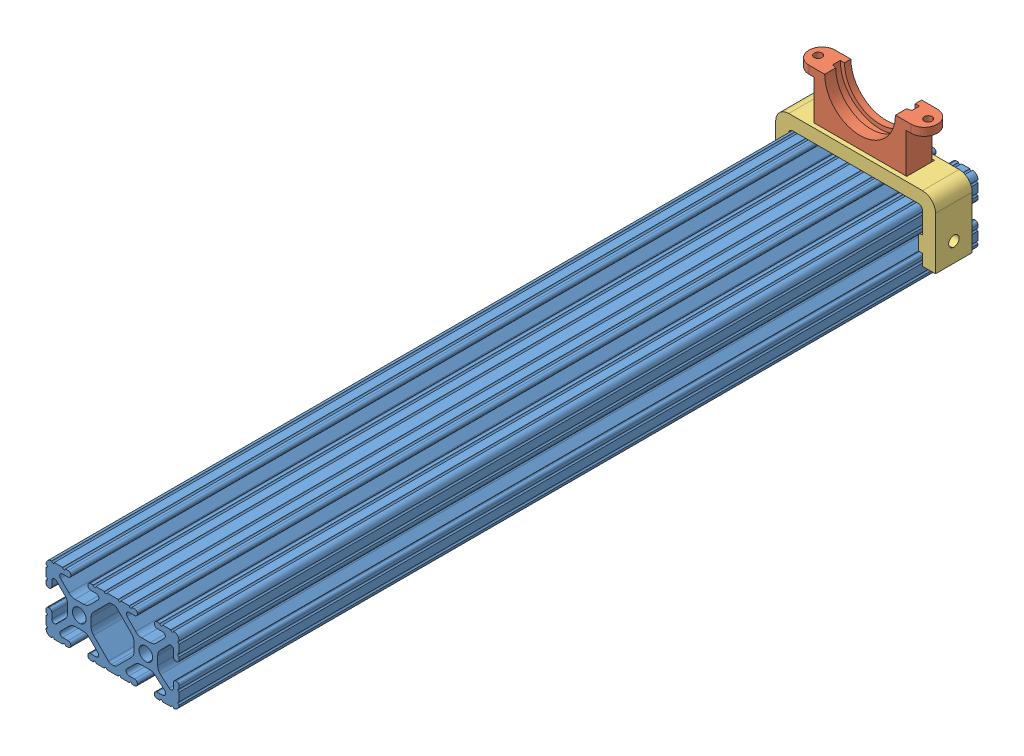
SolidWorks assembly assem, configuration Default. Lengths in mm.
Overall size (61 48.5 304.8).
3 component instances, 3 part files, 7 mates.
Components (placement in the parent):
- 47065T418_ALUMINUM T-SLOTTED FRAMING EXTRUSION-1: 47065T418_ALUMINUM T-SLOTTED FRAMING EXTRUSION [47065T418] at (0 12.7 -152.4) size (50.8 25.4 304.8)
- 300d_100fl_holder-1: 300d_100fl_holder [Default] at (0 48.5 -292.7626) x (0 0 -1) z (1 0 0) size (10 20.1 49)
- tslot_mount-1: tslot_mount [Default] at (0 30.4 -283.4973) x (0 0 -1) z (1 0 0) size (14 25 61)
Mates (geometry in assembly coordinates):
- Coincident2: coincident: point of 47065T418_ALUMINUM T-SLOTTED FRAMING EXTRUSION-1
- Coincident3: coincident aligned: plane of 47065T418_ALUMINUM T-SLOTTED FRAMING EXTRUSION-1 through (0 12.7 -152.4) normal (1 0 0)
- Coincident6: coincident aligned: plane of 300d_100fl_holder-1 through (0 48.5 -292.7626) normal (1 0 0)
- Parallel1: parallel aligned: plane of 47065T418_ALUMINUM T-SLOTTED FRAMING EXTRUSION-1 through (0 12.7 -152.4) normal (0 1 0)
- Coincident11: coincident aligned: plane of tslot_mount-1 through (0 30.4 -283.4973) normal (1 0 0)
- Coincident12: coincident anti-aligned: plane of 47065T418_ALUMINUM T-SLOTTED FRAMING EXTRUSION-1 through (6.3669 25.4 0) normal (0 1 0); plane of tslot_mount-1 through (25.5 25.4 -297.4973) normal (0 -1 0)
- Coincident14: coincident aligned: line of 300d_100fl_holder-1 through (17.5 28.4 -285.1973) axis (-1 0 0); line of tslot_mount-1 through (17.8 28.4 -285.1973) axis (-1 0 0)
